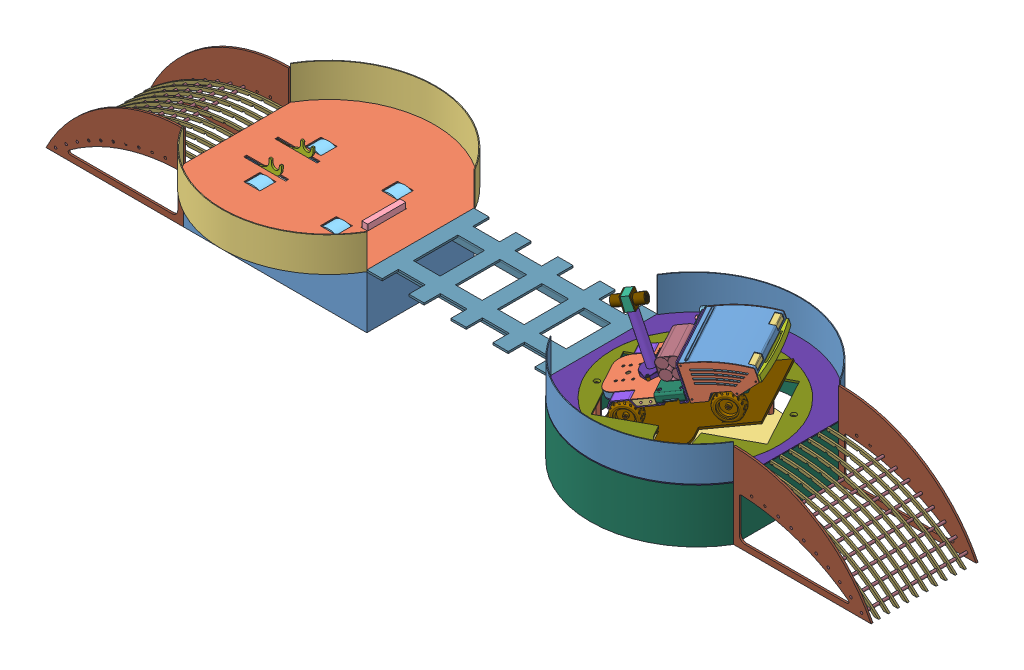
SolidWorks assembly TEST ASSEMBLY, DIAGNOSTIC STATION, configuration Default. Lengths in mm.
Overall size (1371.6 275.63 374.18).
242 component instances, 62 part files, 16 mates.
Components (placement in the parent):
- TOP LEVEL, DYNO STATION-1: TOP LEVEL, DYNO STATION [Default] at origin size (309.34 146.05 355.6)
  - BASE, CHARGING STATION-1: BASE, CHARGING STATION [Default] at (-53.1121 -14.9924 16.6417) size (304.8 88.9 177.8)
  - PLATE, DIAGNOSTIC STATION-1: PLATE, DIAGNOSTIC STATION [Default] at (-53.1121 73.9076 16.6417) size (304.8 1.65 352.87)
  - SIDE, STATION BASE-1: SIDE, STATION BASE [Default] at (-53.1121 73.9076 105.732) size (306.99 57.15 88.71)
  - SIDE, STATION BASE-2: SIDE, STATION BASE [Default] at (-53.1121 73.9076 -72.4486) x (-1 0 0) z (0 0 -1) size (306.99 57.15 88.71)
  - WALL, STATION STOP-1: WALL, STATION STOP [Default] at (38.6454 21.2433 16.6417) size (9.53 63.5 63.5)
  - ROLLER, DYNO-1: ROLLER, DYNO [Default] at (10.3879 51.7461 67.4417) size (50.8 50.8 25)
  - ROLLER, DYNO-2: ROLLER, DYNO [Default] at (10.3879 51.7461 -34.1583) size (50.8 50.8 25)
  - ROLLER, DYNO-3: ROLLER, DYNO [Default] at (-116.6121 51.7461 67.4417) size (50.8 50.8 25)
  - ROLLER, DYNO-4: ROLLER, DYNO [Default] at (-116.6121 51.7461 -34.1583) size (50.8 50.8 25)
  - ENCODER, POLOLU-1: ENCODER, POLOLU [Default] at (-27.7823 50.1586 83.1167) x (0 -1 0) z (1 0 0) size (26.6 2.6 26.04)
  - ENCODER, POLOLU-2: ENCODER, POLOLU [Default] at (-152.4365 50.1586 83.1167) x (0 -1 0) z (1 0 0) size (26.6 2.6 26.04)
  - ENCODER, POLOLU-3: ENCODER, POLOLU [Default] at (-152.4365 50.1586 -49.8333) x (0 1 0) z (1 0 0) size (26.6 2.6 26.04)
  - ENCODER, POLOLU-4: ENCODER, POLOLU [Default] at (-27.7823 50.1586 -49.8333) x (0 1 0) z (1 0 0) size (26.6 2.6 26.04)
  - PLATE, DYNO BRACE-1: PLATE, DYNO BRACE [Default] at (-192.8121 58.6891 -11.1205) x (0.997271 -0.07383 0) z (0 0 1) size (94.55 48.58 3)
  - PLATE, DYNO BRACE-2: PLATE, DYNO BRACE [Default] at (-192.8121 58.6891 41.4067) x (0.997271 -0.07383 0) z (0 0 1) size (94.55 48.58 3)
  - SCOUT, TOP LEVEL-1: SCOUT, TOP LEVEL [Default] at (-30.7092 103.3132 8.7561) x (0 0 -1) z (1 0 0) size (124.43 158.23 223.86) (suppressed, hidden)
    - 6655k13 Thrust Washers-1: 6655k13 Thrust Washers [Default] at (-7.8856 2.7539 2.2902) size (14.15 14.15 4.9)
    - REAR, TOP LEVEL-1: REAR, TOP LEVEL [Default] at (-50.0168 -33.3245 -47.0081) x (-1 0 0) z (0 0 -1) size (124.43 158.23 120.66)
      - PLATE, REAR-1: PLATE, REAR [Default] at (-42.1312 28.0774 12.7174) size (120.65 55.63 120.66)
      - WHEEL ASSEMBLY-1: WHEEL ASSEMBLY [Default-_flexible1] at (7.6153 26.9792 58.7651) x (0 0 1) z (1 0 0) size (42.46 78.6 70.03) (flexible)
        - Pololu 49x19 Wheel-1: Pololu 49x19 Wheel [Default] at (-19.8703 11.8393 2.4418) size (42.46 42.56 19)
        - Pololu Extended Micro Metal Bracket-1: Pololu Extended Micro Metal Bracket [Default] at (-19.8703 6.8393 -18.4366) size (26.6 22.49 26.04)
        - Pololu 298-1 Motor-1: Pololu 298-1 Motor [Default] at (-19.8703 11.8393 -25.1366) x (0 0 -1) z (0 1 0) size (35.87 12 10)
      - WHEEL ASSEMBLY-2: WHEEL ASSEMBLY [Default-_flexible2] at (-91.8778 26.9792 19.0244) x (0 0 -1) z (-1 0 0) size (42.46 78.6 70.03) (flexible)
        - Pololu 49x19 Wheel-1: Pololu 49x19 Wheel [Default] at (-19.8703 11.8393 2.4418) size (42.46 42.56 19)
        - Pololu Extended Micro Metal Bracket-1: Pololu Extended Micro Metal Bracket [Default] at (-19.8703 6.8393 -18.4366) size (26.6 22.49 26.04)
        - Pololu 298-1 Motor-1: Pololu 298-1 Motor [Default] at (-19.8703 11.8393 -25.1366) x (0 0 -1) z (0 1 0) size (35.87 12 10)
      - Socket Head Cap Screw_AI-9: Socket Head Cap Screw_AI [HX-SHCS 0.086-56x0.4375x0.4375-N] at (-77.6912 31.9128 47.8948) x (0 -1 0) z (-0.381305 0 -0.924449) size (13.3 3.56 3.56)
      - Socket Head Cap Screw_AI-10: Socket Head Cap Screw_AI [HX-SHCS 0.086-56x0.4375x0.4375-N] at (-77.6912 31.9128 29.8948) x (0 -1 0) z (0 0 1) size (13.3 3.56 3.56)
      - Socket Head Cap Screw_AI-11: Socket Head Cap Screw_AI [HX-SHCS 0.086-56x0.4375x0.4375-N] at (-6.5712 31.9128 29.8948) x (0 -1 0) z (0 0 1) size (13.3 3.56 3.56)
      - Socket Head Cap Screw_AI-12: Socket Head Cap Screw_AI [HX-SHCS 0.086-56x0.4375x0.4375-N] at (-6.5712 31.9128 47.8948) x (0 -1 0) z (0 0 1) size (13.3 3.56 3.56)
      - 4000mAh 7.4V Battery Pack-1: 4000mAh 7.4V Battery Pack [Default] at (-42.1312 61.2244 -25.7652) x (0 0 -1) z (1 0 0) size (34.29 34.29 68.58)
      - SENSOR, GP2Y0D810-1: SENSOR, GP2Y0D810 [Default] at (9.9271 36.6454 -23.9419) x (0 0 -1) z (0.766044 0.642788 0) size (28.32 10.54 8.89)
      - SENSOR, GP2Y0D810-2: SENSOR, GP2Y0D810 [Default] at (-94.1896 36.6454 -23.9419) x (0 0 -1) z (0.766044 -0.642788 0) size (28.32 10.54 8.89)
      - Battery Support-1: Battery Support [Default] at (-42.1312 29.7284 -26.0192) size (120.65 27.05 38.1)
      - Mounting Block-1: Mounting Block [Default] at (-42.1312 36.0784 -35.6712) x (-1 0 0) z (0 0 -1) size (25.4 12.7 25.4)
      - PF35T-48-1: PF35T-48 [Default] at (-42.1312 31.7284 12.5888) size (50 29.2 35)
      - MaxSonar EZ1-1: MaxSonar EZ1 [Default] at (-42.1312 140.4691 6.6293) x (-1 0 0) z (0 0.034899 -0.999391) size (19.94 22.1 16.38)
      - MaxSonar EZ1-2: MaxSonar EZ1 [Default] at (-42.1312 140.4691 18.5483) x (1 0 0) z (0 0.034899 0.999391) size (19.94 22.1 16.38)
      - BUMPER, REAR-1: BUMPER, REAR [Default] at (-42.1312 29.7284 53.2288) x (-1 0 0) z (0 0 -1) size (80.01 9.53 54.3)
      - PLATE, REAR COVER-1: PLATE, REAR COVER [Default] at (-42.1312 39.2534 72.2788) size (120.65 0.81 81.14)
      - MOUNTING BLOCK, COLOR SENSOR-1: MOUNTING BLOCK, COLOR SENSOR [Default] at (-97.6937 29.7284 5.6038) size (9.53 9.53 30.46)
      - MOUNTING BLOCK, COLOR SENSOR-2: MOUNTING BLOCK, COLOR SENSOR [Default] at (13.4313 29.7284 5.6038) size (9.53 9.53 30.46)
      - SENSOR, COLOR LED-1: SENSOR, COLOR LED [Default] at (-24.0807 23.782 31.9371) x (0 0 -1) z (-0.409692 -0.912224 0) size (5.83 3.66 3.66)
      - SENSOR, COLOR LED-2: SENSOR, COLOR LED [Default] at (-67.3741 22.996 31.9371) x (0 0 -1) z (-0.202984 -0.979182 0) size (5.83 3.66 3.66)
      - COPPER CONTACT-1: COPPER CONTACT [Default] at (-53.2437 34.4909 64.0238) size (15.88 6.35 4.45)
      - COPPER CONTACT-2: COPPER CONTACT [Default] at (-31.0187 34.4909 64.0238) size (15.88 6.35 4.45)
      - MOUNTING BLOCK, SONAR-1: MOUNTING BLOCK, SONAR [Default] at (-42.1312 140.3989 12.5888) x (-1 0 0) z (0 0 -1) size (19.94 22.23 12.7)
      - SHAFT, SONAR MOUNT-1: SHAFT, SONAR MOUNT [Default] at (-42.1312 52.5784 12.5888) x (-0.538443 0 0.842662) z (-0.842662 0 -0.538443) size (4.76 89.41 4.76)
      - SHAFT, SONAR SUPPORT-1: SHAFT, SONAR SUPPORT [Default] at (-42.1312 46.7284 12.5888) x (0.999987 0 0.005105) z (-0.005105 0 0.999987) size (14.22 82.87 14.22)
      - SHAFT, STEPPER SUPPORT-1: SHAFT, STEPPER SUPPORT [Default] at (-63.1312 29.6724 12.5888) size (4.76 16.26 4.76)
      - SHAFT, STEPPER SUPPORT-2: SHAFT, STEPPER SUPPORT [Default] at (-21.1312 29.6724 12.5888) x (0.987866 0 -0.155311) z (0.155311 0 0.987866) size (4.76 16.26 4.76)
      - Flat Head 100 Screw_AI-6: Flat Head 100 Screw_AI [CR-FHM1 0.112-40x0.25x0.25-N] at (-63.1312 46.7284 12.5888) x (0 -1 0) z (0 0 1) size (6.35 4.85 4.85)
      - Flat Head 100 Screw_AI-7: Flat Head 100 Screw_AI [CR-FHM1 0.112-40x0.25x0.25-N] at (-21.1312 46.7284 12.5888) x (0 -1 0) z (0 0 1) size (6.35 4.85 4.85)
      - CONNECTOR, MOLEX 6 PIN-1: CONNECTOR, MOLEX 6 PIN [Default] at (-80.2263 37.7912 12.5433) size (10.34 13.8 9.75)
      - SENSOR, COLOR LED-3: SENSOR, COLOR LED [Default] at (-64.0196 42.7147 3.5765) x (1 0 0) z (0 0.700538 -0.713616) size (5.83 3.66 3.66)
      - SENSOR, COLOR LED-4: SENSOR, COLOR LED [Default] at (-64.0196 42.7147 -9.1235) x (1 0 0) z (0 0.700538 -0.713616) size (5.83 3.66 3.66)
      - SENSOR, COLOR LED-5: SENSOR, COLOR LED [Default] at (-20.2429 42.7147 20.3311) x (-1 0 0) z (0 0.700538 0.713616) size (5.83 3.66 3.66)
      - SENSOR, COLOR LED-6: SENSOR, COLOR LED [Default] at (-20.2429 42.7147 7.6311) x (-1 0 0) z (0 0.700538 0.713616) size (5.83 3.66 3.66)
      - MOUNTING BLOCK, REAR-1: MOUNTING BLOCK, REAR [Default] at (-58.0062 34.4909 31.0038) size (9.53 9.53 28.57)
      - MOUNTING BLOCK, REAR-2: MOUNTING BLOCK, REAR [Default] at (-26.2562 34.4909 31.0038) size (9.53 9.53 28.57)
      - SW3dPS-Sliderswitch-1: SW3dPS-Sliderswitch [Standard] at (-81.1109 44.0794 -21.7288) size (7.4 16 23.2)
    - FRONT, TOP LEVEL-1: FRONT, TOP LEVEL [Default] at (-84.349 -51.7544 28.3431) x (-1 0 0) z (0 0 -1) size (123.38 92.14 123.57)
      - PLATE, FRONT-1: PLATE, FRONT [Default] at (-76.4634 46.5072 -32.0242) size (120.65 12.1 60.8)
      - WHEEL ASSEMBLY-1: WHEEL ASSEMBLY [Default-_flexible3] at (-26.7168 45.4091 2.1802) x (0 0 1) z (1 0 0) size (42.46 78.6 70.03) (flexible)
        - Pololu 49x19 Wheel-1: Pololu 49x19 Wheel [Default] at (-19.8703 11.8393 2.4418) size (42.46 42.56 19)
        - Pololu Extended Micro Metal Bracket-1: Pololu Extended Micro Metal Bracket [Default] at (-19.8703 6.8393 -18.4366) size (26.6 22.49 26.04)
        - Pololu 298-1 Motor-1: Pololu 298-1 Motor [Default] at (-19.8703 11.8393 -25.1366) x (0 0 -1) z (0 1 0) size (35.87 12 10)
      - WHEEL ASSEMBLY-2: WHEEL ASSEMBLY [Default-_flexible4] at (-126.21 45.4091 -37.5605) x (0 0 -1) z (-1 0 0) size (42.46 78.6 70.03) (flexible)
        - Pololu 49x19 Wheel-1: Pololu 49x19 Wheel [Default] at (-19.8703 11.8393 2.4418) size (42.46 42.56 19)
        - Pololu Extended Micro Metal Bracket-1: Pololu Extended Micro Metal Bracket [Default] at (-19.8703 6.8393 -18.4366) size (26.6 22.49 26.04)
        - Pololu 298-1 Motor-1: Pololu 298-1 Motor [Default] at (-19.8703 11.8393 -25.1366) x (0 0 -1) z (0 1 0) size (35.87 12 10)
      - Socket Head Cap Screw_AI-11: Socket Head Cap Screw_AI [HX-SHCS 0.086-56x0.4375x0.4375-N] at (-112.0234 50.3426 -8.6902) x (0 -1 0) z (0.989468 0 0.144748) size (13.3 3.56 3.56)
      - Socket Head Cap Screw_AI-12: Socket Head Cap Screw_AI [HX-SHCS 0.086-56x0.4375x0.4375-N] at (-40.9034 50.3426 -8.6902) x (0 -1 0) z (0.700957 0 0.713204) size (13.3 3.56 3.56)
      - SENSOR, GP2Y0D810-2: SENSOR, GP2Y0D810 [Default] at (-76.7491 52.0249 -21.9932) x (1 0 0) z (0 -0.642788 0.766044) size (28.32 10.54 8.89)
      - BUMPER, FRONT-1: BUMPER, FRONT [Default] at (-76.4634 36.9822 -30.9902) x (-1 0 0) z (0 0 -1) size (69.85 9.53 6.35)
      - Mounting Block-1: Mounting Block [Default] at (-76.4634 54.5082 12.4258) size (25.4 12.7 25.4)
      - Socket Head Shoulder Screw2_AI-2: Socket Head Shoulder Screw2_AI [SHSSCREW 0.25x1.5-N] at (-76.4634 54.5082 2.5706) x (0 0 1) z (-0.728467 -0.685081 0) size (52.4 9.53 9.53)
      - Socket Head Cap Screw_AI-13: Socket Head Cap Screw_AI [HX-SHCS 0.086-56x0.4375x0.4375-N] at (-40.9034 51.2773 -26.6902) x (0 -1 0) z (-0.957829 0 -0.287339) size (13.3 3.56 3.56)
      - Socket Head Cap Screw_AI-14: Socket Head Cap Screw_AI [HX-SHCS 0.086-56x0.4375x0.4375-N] at (-112.0234 51.2773 -26.6902) x (0 -1 0) z (-0.957829 0 -0.287339) size (13.3 3.56 3.56)
      - PCB, MAIN-1: PCB, MAIN [Default] at (-76.4634 67.2082 -21.6044) size (114.3 6.68 88.9)
      - PLATE, FRONT BUMPER-1: PLATE, FRONT BUMPER [Default] at (-76.4634 48.9202 -22.7941) size (120.65 17.91 44.79)
      - COVER, FRONT-1: COVER, FRONT [Default] at (-76.4634 65.9445 25.1258) size (120.65 38.48 93.73)
      - PLATE, FRONT SIDE-1: PLATE, FRONT SIDE [Default] at (-16.1384 46.5072 25.1258) x (0 0 -1) z (1 0 0) size (93.73 55.63 1.27)
      - SW3dPS-USB_mini_B-1: SW3dPS-USB_mini_B [По умолчанию] at (-54.9865 68.8084 -58.5669) x (-1 0 0) z (0 0 -1) (suppressed, hidden)
      - HEADLIGHT COVER, FRONT-1: HEADLIGHT COVER, FRONT [Default] at (-103.1334 74.8345 -67.5842) x (-1 0 0) z (0 0 -1) size (31.75 14.4 11.68)
      - HEADLIGHT COVER, FRONT-2: HEADLIGHT COVER, FRONT [Default] at (-18.0434 74.8345 -67.5842) x (-1 0 0) z (0 0 -1) size (31.75 14.4 11.68)
      - PLATE, FRONT SIDE-2: PLATE, FRONT SIDE [Default] at (-138.0584 46.5072 25.1258) x (0 0 -1) z (1 0 0) size (93.73 55.63 1.27)
      - STRUT, FRONT SIDE-1: STRUT, FRONT SIDE [Default] at (-76.4634 98.9582 21.9508) size (120.65 3.17 6.35)
      - FILTER, FRONT COVER-1: FILTER, FRONT COVER [Default] at (-19.1356 62.8553 14.5951) x (0 0 -1) z (1 0 0) size (76.17 31.33 3)
      - FILTER, FRONT COVER-2: FILTER, FRONT COVER [Default] at (-136.7884 62.8559 13.2551) x (0 0 -1) z (1 0 0) size (76.17 31.33 3)
      - Orb LED-1: Orb LED [Default] at (-118.9744 68.8084 -63.3886) size (6.35 9.53 6.35)
      - Orb LED-2: Orb LED [Default] at (-34.5831 68.8084 -63.3886) size (6.35 9.53 6.35)
    - BUMPER, FRONT SWITCHED-1: BUMPER, FRONT SWITCHED [Default] at (-7.8856 18.9527 98.5308) size (120.65 9.53 7.62)
  - MOUNT, DYNO BRACE-1: MOUNT, DYNO BRACE [Default] at (-203.9246 72.3201 -8.1233) size (25.11 25.11 3)
  - HS-311 Body-1: HS-311 Body [Default] at (14.3249 -4.6899 39.9069) x (0 1 0) z (-1 0 0) size (52.83 41.27 19.56)
  - HS-311-1: HS-311 [Default] at (-146.9221 -64.5715 -52.962) x (0 -1 0) z (-1 0 0) size (53.35 42.67 32.28)
    - HS-311 Body-1: HS-311 Body [Default] at (-132.5316 -0.8305 55.669) size (52.83 41.27 19.56)
    - HS-311 Servo Horn-1: HS-311 Servo Horn [Default] at (-123.2606 39.8095 45.89) x (-0.883566 0 0.468306) z (-0.468306 0 -0.883566) size (23.88 4.83 23.88)
  - MOUNT, DYNO BRACE-2: MOUNT, DYNO BRACE [Default] at (-203.9246 72.3201 44.4039) size (25.11 25.11 3)
- TOP LEVEL, RAMP-3: TOP LEVEL, RAMP [Default] at (-308.1964 -28.4852 45.0895) size (228.6 141.29 177.8)
  - SIDE, RAMP WALL-1: SIDE, RAMP WALL [Default] at (-125.9157 13.4928 57.2772) size (228.6 141.29 3.17)
  - SIDE, RAMP WALL-2: SIDE, RAMP WALL [Default] at (-125.9157 13.4928 -117.3478) size (228.6 141.29 3.17)
  - SLAT, RAMP-1: SLAT, RAMP [Default] at (-125.9157 13.4928 38.2272) size (228.6 90.49 3.17)
  - PIPE, RAMP SLAT-1: PIPE, RAMP SLAT [Default] at (-110.0407 21.2683 -28.4478) size (4.19 4.19 177.8)
  - SLAT, RAMP-2: SLAT, RAMP [Default] at (-125.9157 13.4928 22.3522) size (228.6 90.49 3.17)
  - SLAT, RAMP-3: SLAT, RAMP [Default] at (-125.9157 13.4928 6.4772) size (228.6 90.49 3.17)
  - SLAT, RAMP-4: SLAT, RAMP [Default] at (-125.9157 13.4928 -9.3978) size (228.6 90.49 3.17)
  - SLAT, RAMP-5: SLAT, RAMP [Default] at (-125.9157 13.4928 -25.2728) size (228.6 90.49 3.17)
  - SLAT, RAMP-6: SLAT, RAMP [Default] at (-125.9157 13.4928 -41.1478) size (228.6 90.49 3.17)
  - SLAT, RAMP-7: SLAT, RAMP [Default] at (-125.9157 13.4928 -57.0228) size (228.6 90.49 3.17)
  - SLAT, RAMP-8: SLAT, RAMP [Default] at (-125.9157 13.4928 -72.8978) size (228.6 90.49 3.17)
  - SLAT, RAMP-9: SLAT, RAMP [Default] at (-125.9157 13.4928 -88.7728) size (228.6 90.49 3.17)
  - SLAT, RAMP-10: SLAT, RAMP [Default] at (-125.9157 13.4928 -104.6478) size (228.6 90.49 3.17)
  - PIPE, RAMP SLAT-2: PIPE, RAMP SLAT [Default] at (-92.508 35.1171 -28.4478) x (0.997697 -0.067822 0) z (0 0 1) size (4.19 4.19 177.8)
  - PIPE, RAMP SLAT-3: PIPE, RAMP SLAT [Default] at (-74.0764 47.7449 -28.4478) x (0.9908 -0.135331 0) z (0 0 1) size (4.19 4.19 177.8)
  - PIPE, RAMP SLAT-4: PIPE, RAMP SLAT [Default] at (-54.8308 59.0935 -28.4478) x (0.979341 -0.202218 0) z (0 0 1) size (4.19 4.19 177.8)
  - PIPE, RAMP SLAT-5: PIPE, RAMP SLAT [Default] at (-34.8598 69.1108 -28.4478) x (0.963371 -0.268173 0) z (0 0 1) size (4.19 4.19 177.8)
  - PIPE, RAMP SLAT-6: PIPE, RAMP SLAT [Default] at (-14.2554 77.7505 -28.4478) x (0.942965 -0.332893 0) z (0 0 1) size (4.19 4.19 177.8)
  - PIPE, RAMP SLAT-7: PIPE, RAMP SLAT [Default] at (6.8875 84.9729 -28.4478) x (0.918216 -0.39608 0) z (0 0 1) size (4.19 4.19 177.8)
  - PIPE, RAMP SLAT-8: PIPE, RAMP SLAT [Default] at (28.4716 90.7447 -28.4478) x (0.889239 -0.457443 0) z (0 0 1) size (4.19 4.19 177.8)
- STRUTS, CLIFF SENSOR-1: STRUTS, CLIFF SENSOR [Default] at (251.6879 72.3836 16.6417) size (304.8 12.7 177.8)
- TOP LEVEL, RAMP-5: TOP LEVEL, RAMP [Default] at (811.5722 -28.4852 -11.8061) x (-1 0 0) z (0 0 -1) size (228.6 141.29 177.8)
  - SIDE, RAMP WALL-1: SIDE, RAMP WALL [Default] at (-125.9157 13.4928 57.2772) size (228.6 141.29 3.17)
  - SIDE, RAMP WALL-2: SIDE, RAMP WALL [Default] at (-125.9157 13.4928 -117.3478) size (228.6 141.29 3.17)
  - SLAT, RAMP-1: SLAT, RAMP [Default] at (-125.9157 13.4928 38.2272) size (228.6 90.49 3.17)
  - PIPE, RAMP SLAT-1: PIPE, RAMP SLAT [Default] at (-110.0407 21.2683 -28.4478) size (4.19 4.19 177.8)
  - SLAT, RAMP-2: SLAT, RAMP [Default] at (-125.9157 13.4928 22.3522) size (228.6 90.49 3.17)
  - SLAT, RAMP-3: SLAT, RAMP [Default] at (-125.9157 13.4928 6.4772) size (228.6 90.49 3.17)
  - SLAT, RAMP-4: SLAT, RAMP [Default] at (-125.9157 13.4928 -9.3978) size (228.6 90.49 3.17)
  - SLAT, RAMP-5: SLAT, RAMP [Default] at (-125.9157 13.4928 -25.2728) size (228.6 90.49 3.17)
  - SLAT, RAMP-6: SLAT, RAMP [Default] at (-125.9157 13.4928 -41.1478) size (228.6 90.49 3.17)
  - SLAT, RAMP-7: SLAT, RAMP [Default] at (-125.9157 13.4928 -57.0228) size (228.6 90.49 3.17)
  - SLAT, RAMP-8: SLAT, RAMP [Default] at (-125.9157 13.4928 -72.8978) size (228.6 90.49 3.17)
  - SLAT, RAMP-9: SLAT, RAMP [Default] at (-125.9157 13.4928 -88.7728) size (228.6 90.49 3.17)
  - SLAT, RAMP-10: SLAT, RAMP [Default] at (-125.9157 13.4928 -104.6478) size (228.6 90.49 3.17)
  - PIPE, RAMP SLAT-2: PIPE, RAMP SLAT [Default] at (-92.508 35.1171 -28.4478) x (0.997697 -0.067822 0) z (0 0 1) size (4.19 4.19 177.8)
  - PIPE, RAMP SLAT-3: PIPE, RAMP SLAT [Default] at (-74.0764 47.7449 -28.4478) x (0.9908 -0.135331 0) z (0 0 1) size (4.19 4.19 177.8)
  - PIPE, RAMP SLAT-4: PIPE, RAMP SLAT [Default] at (-54.8308 59.0935 -28.4478) x (0.979341 -0.202218 0) z (0 0 1) size (4.19 4.19 177.8)
  - PIPE, RAMP SLAT-5: PIPE, RAMP SLAT [Default] at (-34.8598 69.1108 -28.4478) x (0.963371 -0.268173 0) z (0 0 1) size (4.19 4.19 177.8)
  - PIPE, RAMP SLAT-6: PIPE, RAMP SLAT [Default] at (-14.2554 77.7505 -28.4478) x (0.942965 -0.332893 0) z (0 0 1) size (4.19 4.19 177.8)
  - PIPE, RAMP SLAT-7: PIPE, RAMP SLAT [Default] at (6.8875 84.9729 -28.4478) x (0.918216 -0.39608 0) z (0 0 1) size (4.19 4.19 177.8)
  - PIPE, RAMP SLAT-8: PIPE, RAMP SLAT [Default] at (28.4716 90.7447 -28.4478) x (0.889239 -0.457443 0) z (0 0 1) size (4.19 4.19 177.8)
- TOP LEVEL, GYRO STATION-1: TOP LEVEL, GYRO STATION [Default] at (648.2759 27.4625 -39.0664) size (374.18 275.63 374.18)
  - BASE, GYRO STATION-1: BASE, GYRO STATION [Default] at (-91.788 -42.4549 55.708) size (304.8 88.9 350.24)
  - PLATE, GYRO STATION-1: PLATE, GYRO STATION [Default] at (-91.788 44.9211 55.708) x (-0.878417 0 0.477895) z (-0.477895 0 -0.878417) size (275.88 3.17 275.88)
  - PLATE, GYRO STATION PLATFORM-1: PLATE, GYRO STATION PLATFORM [Default] at (-91.788 46.4451 55.708) size (304.8 1.65 350.24)
  - PLATE, GYRO TILT-1: PLATE, GYRO TILT [Default] at (-91.788 44.9211 55.708) x (-0.839245 -0.295295 0.456584) z (-0.477895 0 -0.878417) size (212.73 3.18 222.25)
  - SIDE, GYRO STATION BASE-1: SIDE, GYRO STATION BASE [Default] at (-91.788 48.0961 144.608) size (304.8 57.15 86.87)
  - SIDE, GYRO STATION BASE-2: SIDE, GYRO STATION BASE [Default] at (-91.788 48.0961 -33.192) x (-1 0 0) z (0 0 -1) size (304.8 57.15 86.87)
  - STANDOFF, GYRO STATIOn-1: STANDOFF, GYRO STATIOn [Default] at (-197.769 6.8211 113.3661) x (-0.664708 0 0.747103) z (-0.747103 0 -0.664708) size (10.54 76.2 10.7)
  - STANDOFF, GYRO STATIOn-2: STANDOFF, GYRO STATIOn [Default] at (-194.7119 6.8211 -7.2452) x (-0.979364 0 -0.202103) z (0.202103 0 -0.979364) size (10.54 76.2 10.7)
  - STANDOFF, GYRO STATIOn-3: STANDOFF, GYRO STATIOn [Default] at (-88.7309 6.8211 -64.9032) x (-0.314656 0 -0.949206) z (0.949206 0 -0.314656) size (10.54 76.2 10.7)
  - STANDOFF, GYRO STATIOn-4: STANDOFF, GYRO STATIOn [Default] at (14.1929 6.8211 -1.95) x (0.664708 0 -0.747103) z (0.747103 0 0.664708) size (10.54 76.2 10.7)
  - STANDOFF, GYRO STATIOn-5: STANDOFF, GYRO STATIOn [Default] at (11.1358 6.8211 118.6612) x (0.979364 0 0.202103) z (-0.202103 0 0.979364) size (10.54 76.2 10.7)
  - STANDOFF, GYRO STATIOn-6: STANDOFF, GYRO STATIOn [Default] at (-94.8452 6.8211 176.3193) x (0.314656 0 0.949206) z (-0.949206 0 0.314656) size (10.54 76.2 10.7)
  - PLATE, GYRO STATION BASE-1: PLATE, GYRO STATION BASE [Default] at (-91.788 -34.4539 55.708) x (-0.025339 0 0.999679) z (-0.999679 0 -0.025339) size (260.35 3.17 260.35)
  - STRUT, GYRO LOCK-1: STRUT, GYRO LOCK [Default] at (-124.1863 26.2999 -22.4506) x (-0.839245 -0.295295 0.456584) z (-0.477895 0 -0.878417) size (3 88.9 6.35)
  - STRUT, GYRO LOCK-2: STRUT, GYRO LOCK [Default] at (-129.217 24.5298 -19.7136) x (-0.839245 -0.295295 0.456584) z (-0.477895 0 -0.878417) size (3 88.9 6.35)
  - STRUT, VERTICAL, GYRO LOCK-1: STRUT, VERTICAL, GYRO LOCK [Default] at (-144.4175 52.0621 -33.1292) x (-0.839245 -0.295295 0.456584) z (-0.477895 0 -0.878417) size (3 60.33 9.53)
  - STRUT, VERTICAL, GYRO LOCK-2: STRUT, VERTICAL, GYRO LOCK [Default] at (-146.9329 51.1771 -31.7607) x (-0.839245 -0.295295 0.456584) z (-0.477895 0 -0.878417) size (3 60.33 9.53)
  - ARM, GYRO LOCK-1: ARM, GYRO LOCK [Default] at (-156.3369 101.0393 -26.6446) x (0.474857 0.011073 0.879993) z (-0.839245 -0.295295 0.456584) size (66.26 12.7 3)
  - SCOUT, TOP LEVEL-1: SCOUT, TOP LEVEL [Default] at (-88.6008 88.8309 44.997) x (-0.477895 0 -0.878417) z (0.839245 0.295295 -0.456584) size (124.43 158.23 223.86)
    - 6655k13 Thrust Washers-1: 6655k13 Thrust Washers [Default] at (-7.8856 2.7539 2.2902) size (14.15 14.15 4.9)
    - REAR, TOP LEVEL-1: REAR, TOP LEVEL [Default] at (-50.0168 -33.3245 -47.0081) x (-1 0 0) z (0 0 -1) size (124.43 158.23 120.66)
      - PLATE, REAR-1: PLATE, REAR [Default] at (-42.1312 28.0774 12.7174) size (120.65 55.63 120.66)
      - WHEEL ASSEMBLY-1: WHEEL ASSEMBLY [Default-_flexible1] at (7.6153 26.9792 58.7651) x (0 0 1) z (1 0 0) size (42.46 78.6 70.03) (flexible)
        - Pololu 49x19 Wheel-1: Pololu 49x19 Wheel [Default] at (-19.8703 11.8393 2.4418) size (42.46 42.56 19)
        - Pololu Extended Micro Metal Bracket-1: Pololu Extended Micro Metal Bracket [Default] at (-19.8703 6.8393 -18.4366) size (26.6 22.49 26.04)
        - Pololu 298-1 Motor-1: Pololu 298-1 Motor [Default] at (-19.8703 11.8393 -25.1366) x (0 0 -1) z (0 1 0) size (35.87 12 10)
      - WHEEL ASSEMBLY-2: WHEEL ASSEMBLY [Default-_flexible2] at (-91.8778 26.9792 19.0244) x (0 0 -1) z (-1 0 0) size (42.46 78.6 70.03) (flexible)
        - Pololu 49x19 Wheel-1: Pololu 49x19 Wheel [Default] at (-19.8703 11.8393 2.4418) size (42.46 42.56 19)
        - Pololu Extended Micro Metal Bracket-1: Pololu Extended Micro Metal Bracket [Default] at (-19.8703 6.8393 -18.4366) size (26.6 22.49 26.04)
        - Pololu 298-1 Motor-1: Pololu 298-1 Motor [Default] at (-19.8703 11.8393 -25.1366) x (0 0 -1) z (0 1 0) size (35.87 12 10)
      - Socket Head Cap Screw_AI-9: Socket Head Cap Screw_AI [HX-SHCS 0.086-56x0.4375x0.4375-N] at (-77.6912 31.9128 47.8948) x (0 -1 0) z (-0.381305 0 -0.924449) size (13.3 3.56 3.56)
      - Socket Head Cap Screw_AI-10: Socket Head Cap Screw_AI [HX-SHCS 0.086-56x0.4375x0.4375-N] at (-77.6912 31.9128 29.8948) x (0 -1 0) z (0 0 1) size (13.3 3.56 3.56)
      - Socket Head Cap Screw_AI-11: Socket Head Cap Screw_AI [HX-SHCS 0.086-56x0.4375x0.4375-N] at (-6.5712 31.9128 29.8948) x (0 -1 0) z (0 0 1) size (13.3 3.56 3.56)
      - Socket Head Cap Screw_AI-12: Socket Head Cap Screw_AI [HX-SHCS 0.086-56x0.4375x0.4375-N] at (-6.5712 31.9128 47.8948) x (0 -1 0) z (0 0 1) size (13.3 3.56 3.56)
      - 4000mAh 7.4V Battery Pack-1: 4000mAh 7.4V Battery Pack [Default] at (-42.1312 61.2244 -25.7652) x (0 0 -1) z (1 0 0) size (34.29 34.29 68.58)
      - SENSOR, GP2Y0D810-1: SENSOR, GP2Y0D810 [Default] at (9.9271 36.6454 -23.9419) x (0 0 -1) z (0.766044 0.642788 0) size (28.32 10.54 8.89)
      - SENSOR, GP2Y0D810-2: SENSOR, GP2Y0D810 [Default] at (-94.1896 36.6454 -23.9419) x (0 0 -1) z (0.766044 -0.642788 0) size (28.32 10.54 8.89)
      - Battery Support-1: Battery Support [Default] at (-42.1312 29.7284 -26.0192) size (120.65 27.05 38.1)
      - Mounting Block-1: Mounting Block [Default] at (-42.1312 36.0784 -35.6712) x (-1 0 0) z (0 0 -1) size (25.4 12.7 25.4)
      - PF35T-48-1: PF35T-48 [Default] at (-42.1312 31.7284 12.5888) size (50 29.2 35)
      - MaxSonar EZ1-1: MaxSonar EZ1 [Default] at (-42.1312 140.4691 6.6293) x (-1 0 0) z (0 0.034899 -0.999391) size (19.94 22.1 16.38)
      - MaxSonar EZ1-2: MaxSonar EZ1 [Default] at (-42.1312 140.4691 18.5483) x (1 0 0) z (0 0.034899 0.999391) size (19.94 22.1 16.38)
      - BUMPER, REAR-1: BUMPER, REAR [Default] at (-42.1312 29.7284 53.2288) x (-1 0 0) z (0 0 -1) size (80.01 9.53 54.3)
      - PLATE, REAR COVER-1: PLATE, REAR COVER [Default] at (-42.1312 39.2534 72.2788) size (120.65 0.81 81.14)
      - MOUNTING BLOCK, COLOR SENSOR-1: MOUNTING BLOCK, COLOR SENSOR [Default] at (-97.6937 29.7284 5.6038) size (9.53 9.53 30.46)
      - MOUNTING BLOCK, COLOR SENSOR-2: MOUNTING BLOCK, COLOR SENSOR [Default] at (13.4313 29.7284 5.6038) size (9.53 9.53 30.46)
      - SENSOR, COLOR LED-1: SENSOR, COLOR LED [Default] at (-24.0807 23.782 31.9371) x (0 0 -1) z (-0.409692 -0.912224 0) size (5.83 3.66 3.66)
      - SENSOR, COLOR LED-2: SENSOR, COLOR LED [Default] at (-67.3741 22.996 31.9371) x (0 0 -1) z (-0.202984 -0.979182 0) size (5.83 3.66 3.66)
      - COPPER CONTACT-1: COPPER CONTACT [Default] at (-53.2437 34.4909 64.0238) size (15.88 6.35 4.45)
      - COPPER CONTACT-2: COPPER CONTACT [Default] at (-31.0187 34.4909 64.0238) size (15.88 6.35 4.45)
      - MOUNTING BLOCK, SONAR-1: MOUNTING BLOCK, SONAR [Default] at (-42.1312 140.3989 12.5888) x (-1 0 0) z (0 0 -1) size (19.94 22.23 12.7)
      - SHAFT, SONAR MOUNT-1: SHAFT, SONAR MOUNT [Default] at (-42.1312 52.5784 12.5888) x (-0.538443 0 0.842662) z (-0.842662 0 -0.538443) size (4.76 89.41 4.76)
      - SHAFT, SONAR SUPPORT-1: SHAFT, SONAR SUPPORT [Default] at (-42.1312 46.7284 12.5888) x (0.999987 0 0.005105) z (-0.005105 0 0.999987) size (14.22 82.87 14.22)
      - SHAFT, STEPPER SUPPORT-1: SHAFT, STEPPER SUPPORT [Default] at (-63.1312 29.6724 12.5888) size (4.76 16.26 4.76)
      - SHAFT, STEPPER SUPPORT-2: SHAFT, STEPPER SUPPORT [Default] at (-21.1312 29.6724 12.5888) x (0.987866 0 -0.155311) z (0.155311 0 0.987866) size (4.76 16.26 4.76)
      - Flat Head 100 Screw_AI-6: Flat Head 100 Screw_AI [CR-FHM1 0.112-40x0.25x0.25-N] at (-63.1312 46.7284 12.5888) x (0 -1 0) z (0 0 1) size (6.35 4.85 4.85)
      - Flat Head 100 Screw_AI-7: Flat Head 100 Screw_AI [CR-FHM1 0.112-40x0.25x0.25-N] at (-21.1312 46.7284 12.5888) x (0 -1 0) z (0 0 1) size (6.35 4.85 4.85)
      - CONNECTOR, MOLEX 6 PIN-1: CONNECTOR, MOLEX 6 PIN [Default] at (-80.2263 37.7912 12.5433) size (10.34 13.8 9.75)
      - SENSOR, COLOR LED-3: SENSOR, COLOR LED [Default] at (-64.0196 42.7147 3.5765) x (1 0 0) z (0 0.700538 -0.713616) size (5.83 3.66 3.66)
      - SENSOR, COLOR LED-4: SENSOR, COLOR LED [Default] at (-64.0196 42.7147 -9.1235) x (1 0 0) z (0 0.700538 -0.713616) size (5.83 3.66 3.66)
      - SENSOR, COLOR LED-5: SENSOR, COLOR LED [Default] at (-20.2429 42.7147 20.3311) x (-1 0 0) z (0 0.700538 0.713616) size (5.83 3.66 3.66)
      - SENSOR, COLOR LED-6: SENSOR, COLOR LED [Default] at (-20.2429 42.7147 7.6311) x (-1 0 0) z (0 0.700538 0.713616) size (5.83 3.66 3.66)
      - MOUNTING BLOCK, REAR-1: MOUNTING BLOCK, REAR [Default] at (-58.0062 34.4909 31.0038) size (9.53 9.53 28.57)
      - MOUNTING BLOCK, REAR-2: MOUNTING BLOCK, REAR [Default] at (-26.2562 34.4909 31.0038) size (9.53 9.53 28.57)
      - SW3dPS-Sliderswitch-1: SW3dPS-Sliderswitch [Standard] at (-81.1109 44.0794 -21.7288) size (7.4 16 23.2)
    - FRONT, TOP LEVEL-1: FRONT, TOP LEVEL [Default] at (-84.349 -51.7544 28.3431) x (-1 0 0) z (0 0 -1) size (123.38 92.14 123.57)
      - PLATE, FRONT-1: PLATE, FRONT [Default] at (-76.4634 46.5072 -32.0242) size (120.65 12.1 60.8)
      - WHEEL ASSEMBLY-1: WHEEL ASSEMBLY [Default-_flexible3] at (-26.7168 45.4091 2.1802) x (0 0 1) z (1 0 0) size (42.46 78.6 70.03) (flexible)
        - Pololu 49x19 Wheel-1: Pololu 49x19 Wheel [Default] at (-19.8703 11.8393 2.4418) size (42.46 42.56 19)
        - Pololu Extended Micro Metal Bracket-1: Pololu Extended Micro Metal Bracket [Default] at (-19.8703 6.8393 -18.4366) size (26.6 22.49 26.04)
        - Pololu 298-1 Motor-1: Pololu 298-1 Motor [Default] at (-19.8703 11.8393 -25.1366) x (0 0 -1) z (0 1 0) size (35.87 12 10)
      - WHEEL ASSEMBLY-2: WHEEL ASSEMBLY [Default-_flexible4] at (-126.21 45.4091 -37.5605) x (0 0 -1) z (-1 0 0) size (42.46 78.6 70.03) (flexible)
        - Pololu 49x19 Wheel-1: Pololu 49x19 Wheel [Default] at (-19.8703 11.8393 2.4418) size (42.46 42.56 19)
        - Pololu Extended Micro Metal Bracket-1: Pololu Extended Micro Metal Bracket [Default] at (-19.8703 6.8393 -18.4366) size (26.6 22.49 26.04)
        - Pololu 298-1 Motor-1: Pololu 298-1 Motor [Default] at (-19.8703 11.8393 -25.1366) x (0 0 -1) z (0 1 0) size (35.87 12 10)
      - Socket Head Cap Screw_AI-11: Socket Head Cap Screw_AI [HX-SHCS 0.086-56x0.4375x0.4375-N] at (-112.0234 50.3426 -8.6902) x (0 -1 0) z (0.989468 0 0.144748) size (13.3 3.56 3.56)
      - Socket Head Cap Screw_AI-12: Socket Head Cap Screw_AI [HX-SHCS 0.086-56x0.4375x0.4375-N] at (-40.9034 50.3426 -8.6902) x (0 -1 0) z (0.700957 0 0.713204) size (13.3 3.56 3.56)
      - SENSOR, GP2Y0D810-2: SENSOR, GP2Y0D810 [Default] at (-76.7491 52.0249 -21.9932) x (1 0 0) z (0 -0.642788 0.766044) size (28.32 10.54 8.89)
      - BUMPER, FRONT-1: BUMPER, FRONT [Default] at (-76.4634 36.9822 -30.9902) x (-1 0 0) z (0 0 -1) size (69.85 9.53 6.35)
      - Mounting Block-1: Mounting Block [Default] at (-76.4634 54.5082 12.4258) size (25.4 12.7 25.4)
      - Socket Head Shoulder Screw2_AI-2: Socket Head Shoulder Screw2_AI [SHSSCREW 0.25x1.5-N] at (-76.4634 54.5082 2.5706) x (0 0 1) z (-0.728467 -0.685081 0) size (52.4 9.53 9.53)
      - Socket Head Cap Screw_AI-13: Socket Head Cap Screw_AI [HX-SHCS 0.086-56x0.4375x0.4375-N] at (-40.9034 51.2773 -26.6902) x (0 -1 0) z (-0.957829 0 -0.287339) size (13.3 3.56 3.56)
      - Socket Head Cap Screw_AI-14: Socket Head Cap Screw_AI [HX-SHCS 0.086-56x0.4375x0.4375-N] at (-112.0234 51.2773 -26.6902) x (0 -1 0) z (-0.957829 0 -0.287339) size (13.3 3.56 3.56)
      - PCB, MAIN-1: PCB, MAIN [Default] at (-76.4634 67.2082 -21.6044) size (114.3 6.68 88.9)
      - PLATE, FRONT BUMPER-1: PLATE, FRONT BUMPER [Default] at (-76.4634 48.9202 -22.7941) size (120.65 17.91 44.79)
      - COVER, FRONT-1: COVER, FRONT [Default] at (-76.4634 65.9445 25.1258) size (120.65 38.48 93.73)
      - PLATE, FRONT SIDE-1: PLATE, FRONT SIDE [Default] at (-16.1384 46.5072 25.1258) x (0 0 -1) z (1 0 0) size (93.73 55.63 1.27)
      - SW3dPS-USB_mini_B-1: SW3dPS-USB_mini_B [По умолчанию] at (-54.9865 68.8084 -58.5669) x (-1 0 0) z (0 0 -1) (suppressed, hidden)
      - HEADLIGHT COVER, FRONT-1: HEADLIGHT COVER, FRONT [Default] at (-103.1334 74.8345 -67.5842) x (-1 0 0) z (0 0 -1) size (31.75 14.4 11.68)
      - HEADLIGHT COVER, FRONT-2: HEADLIGHT COVER, FRONT [Default] at (-18.0434 74.8345 -67.5842) x (-1 0 0) z (0 0 -1) size (31.75 14.4 11.68)
      - PLATE, FRONT SIDE-2: PLATE, FRONT SIDE [Default] at (-138.0584 46.5072 25.1258) x (0 0 -1) z (1 0 0) size (93.73 55.63 1.27)
      - STRUT, FRONT SIDE-1: STRUT, FRONT SIDE [Default] at (-76.4634 98.9582 21.9508) size (120.65 3.17 6.35)
      - FILTER, FRONT COVER-1: FILTER, FRONT COVER [Default] at (-19.1356 62.8553 14.5951) x (0 0 -1) z (1 0 0) size (76.17 31.33 3)
      - FILTER, FRONT COVER-2: FILTER, FRONT COVER [Default] at (-136.7884 62.8559 13.2551) x (0 0 -1) z (1 0 0) size (76.17 31.33 3)
      - Orb LED-1: Orb LED [Default] at (-118.9744 68.8084 -63.3886) size (6.35 9.53 6.35)
      - Orb LED-2: Orb LED [Default] at (-34.5831 68.8084 -63.3886) size (6.35 9.53 6.35)
    - BUMPER, FRONT SWITCHED-1: BUMPER, FRONT SWITCHED [Default] at (-7.8856 18.9527 98.5308) size (120.65 9.53 7.62)
Mates (geometry in assembly coordinates):
- Coincident53: coincident aligned: plane of TOP LEVEL, RAMP-3/SIDE, RAMP WALL-1 through (-434.1121 -14.9924 105.5417) normal (0 -1 0); plane of TOP LEVEL, RAMP-5/SIDE, RAMP WALL-2 through (937.4879 -14.9924 102.3667) normal (0 -1 0)
- Coincident54: coincident aligned: plane of ? through (-216.4483 -96.8308 148.5878) normal (0 0 1); plane of ? through (647.1517 -96.8308 148.5878) normal (0 0 1)
- Coincident67: coincident aligned: plane of STRUTS, CLIFF SENSOR-1 through (404.0879 75.5586 -20.2708) normal (0 1 0); plane of TOP LEVEL, GYRO STATION-1/PLATE, GYRO STATION PLATFORM-1 through (556.4879 75.5586 19.3227) normal (0 1 0)
- Coincident69: coincident anti-aligned: plane of STRUTS, CLIFF SENSOR-1 through (404.0879 75.5586 -45.2708) normal (1 0 0); plane of TOP LEVEL, GYRO STATION-1/BASE, GYRO STATION-1 through (404.0879 73.9076 105.5417) normal (-1 0 0)
- Coincident70: coincident anti-aligned: plane of TOP LEVEL, RAMP-5/SIDE, RAMP WALL-2 through (708.8879 75.4951 102.3667) normal (-1 0 0); plane of TOP LEVEL, GYRO STATION-1/BASE, GYRO STATION-1 through (708.8879 73.9076 105.5417) normal (1 0 0)
- Coincident73: coincident aligned: plane of TOP LEVEL, DYNO STATION-1 through (0 0 0) normal (1 0 0); plane of assembly
- Coincident74: coincident aligned: plane of TOP LEVEL, DYNO STATION-1 through (0 0 0) normal (0 1 0); plane of assembly
- Coincident75: coincident aligned: plane of TOP LEVEL, DYNO STATION-1 through (0 0 0) normal (0 0 1); plane of assembly
- Coincident76: coincident anti-aligned: plane of TOP LEVEL, DYNO STATION-1/BASE, CHARGING STATION-1 through (-205.5121 73.9076 -72.2583) normal (-1 0 0); plane of TOP LEVEL, RAMP-3/SIDE, RAMP WALL-1 through (-205.5121 75.4951 105.5417) normal (1 0 0)
- Coincident77: coincident aligned: plane of TOP LEVEL, DYNO STATION-1/BASE, CHARGING STATION-1 through (-205.5121 73.9076 105.5417) normal (0 0 1); plane of TOP LEVEL, RAMP-3/SIDE, RAMP WALL-1 through (-205.5121 -258.5066 105.5417) normal (0 0 1)
- Coincident78: coincident aligned: plane of TOP LEVEL, DYNO STATION-1/BASE, CHARGING STATION-1 through (99.2879 -14.9924 105.5417) normal (0 -1 0); plane of TOP LEVEL, RAMP-3/SIDE, RAMP WALL-1 through (-434.1121 -14.9924 105.5417) normal (0 -1 0)
- Coincident79: coincident anti-aligned: plane of TOP LEVEL, DYNO STATION-1/BASE, CHARGING STATION-1 through (99.2879 73.9076 -72.2583) normal (1 0 0); plane of STRUTS, CLIFF SENSOR-1 through (99.2879 62.8586 -20.2708) normal (-1 0 0)
- Coincident80: coincident aligned: plane of TOP LEVEL, DYNO STATION-1/PLATE, DIAGNOSTIC STATION-1 through (-53.1121 75.5586 16.6417) normal (0 1 0); plane of STRUTS, CLIFF SENSOR-1 through (404.0879 75.5586 -20.2708) normal (0 1 0)
- Coincident81: coincident aligned: plane of TOP LEVEL, DYNO STATION-1/BASE, CHARGING STATION-1 through (-205.5121 73.9076 -72.2583) normal (0 0 -1); plane of STRUTS, CLIFF SENSOR-1 through (99.2879 72.3836 -72.2583) normal (0 0 -1)
- Coincident83: coincident: plane of STRUTS, CLIFF SENSOR-1 through (378.6879 72.3836 -72.2583) normal (0 0 -1); line of TOP LEVEL, GYRO STATION-1/BASE, GYRO STATION-1 through (404.0879 73.9076 -72.2583) axis (0 -1 0)
- Coincident84: coincident: plane of TOP LEVEL, RAMP-5/SIDE, RAMP WALL-1 through (708.8879 -258.5066 -72.2583) normal (0 0 -1); line of TOP LEVEL, GYRO STATION-1/BASE, GYRO STATION-1 through (708.8879 73.9076 -72.2583) axis (0 -1 0)
